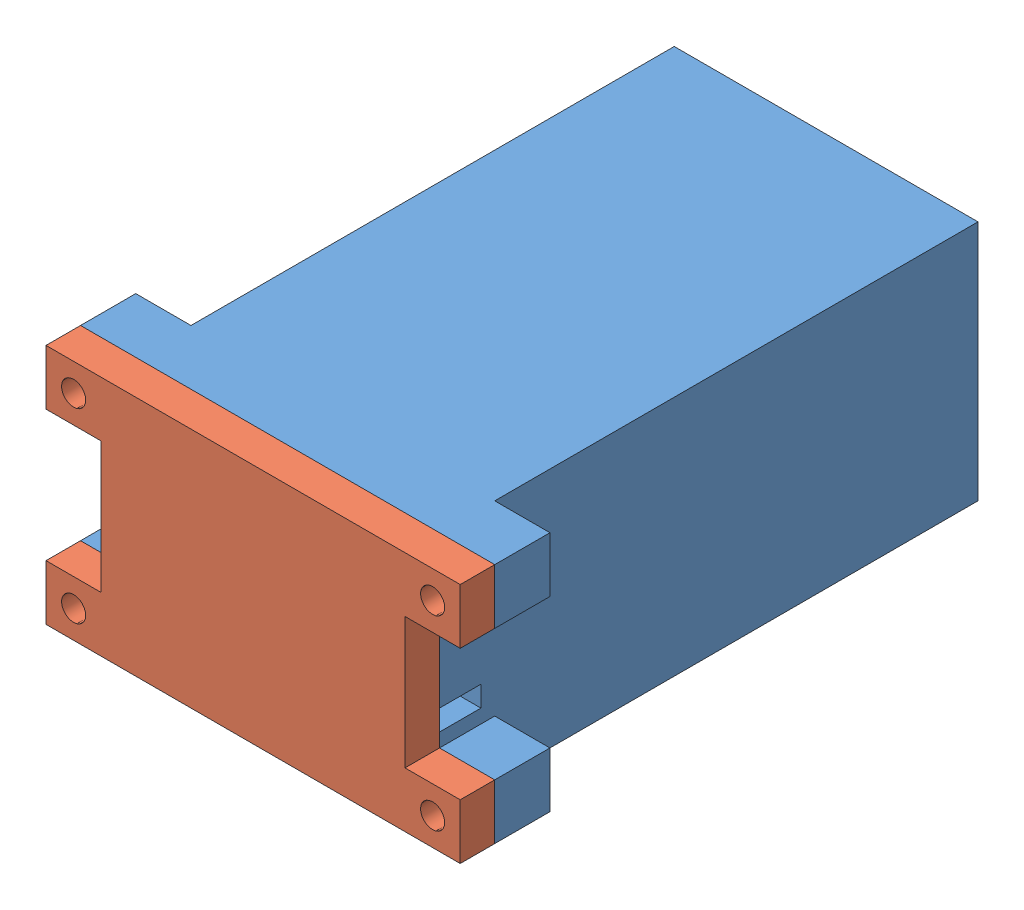
SolidWorks assembly battery_box_7V4, configuration 預設. Lengths in mm.
Overall size (60 35 83).
3 component instances, 3 part files, 5 mates.
Components (placement in the parent):
- battery_box_7V4-1: battery_box_7V4 [預設] at (4.9748 -22.7044 78) size (60 35 78)
- battery_cap_7V4-1: battery_cap_7V4 [預設] at (4.9748 -5.2044 117) size (60 35 5)
- battery7_4Vmodel-1: battery7_4Vmodel [預設] at (4.9748 -2.7044 74.5) x (0 0 1) z (0 -1 0) size (78 38 20)
Mates (geometry in assembly coordinates):
- 重合/共線/共點1: coincident aligned: circle of battery_box_7V4-1; circle of battery_cap_7V4-1
- 同軸心1: concentric anti-aligned: cylinder of battery_box_7V4-1 through (30.9748 8.2956 109) axis (0 0 1) radius 1.75; cylinder of battery_cap_7V4-1 through (30.9748 8.2956 122) axis (0 0 -1) radius 1.75
- 重合/共線/共點2: coincident anti-aligned: plane of battery_box_7V4-1 through (-14.0252 12.2956 39) normal (1 0 0); plane of battery7_4Vmodel-1 through (-14.0252 -12.7044 42) normal (-1 0 0)
- 重合/共線/共點3: coincident anti-aligned: plane of battery_box_7V4-1 through (4.9748 -12.7044 78) normal (0 1 0); plane of battery7_4Vmodel-1 through (4.9748 -12.7044 74.5) normal (0 -1 0)
- 重合/共線/共點4: coincident anti-aligned: plane of battery_box_7V4-1 through (-17.0252 12.2956 42) normal (0 0 1); plane of battery7_4Vmodel-1 through (-14.0252 -12.7044 42) normal (0 0 -1)
